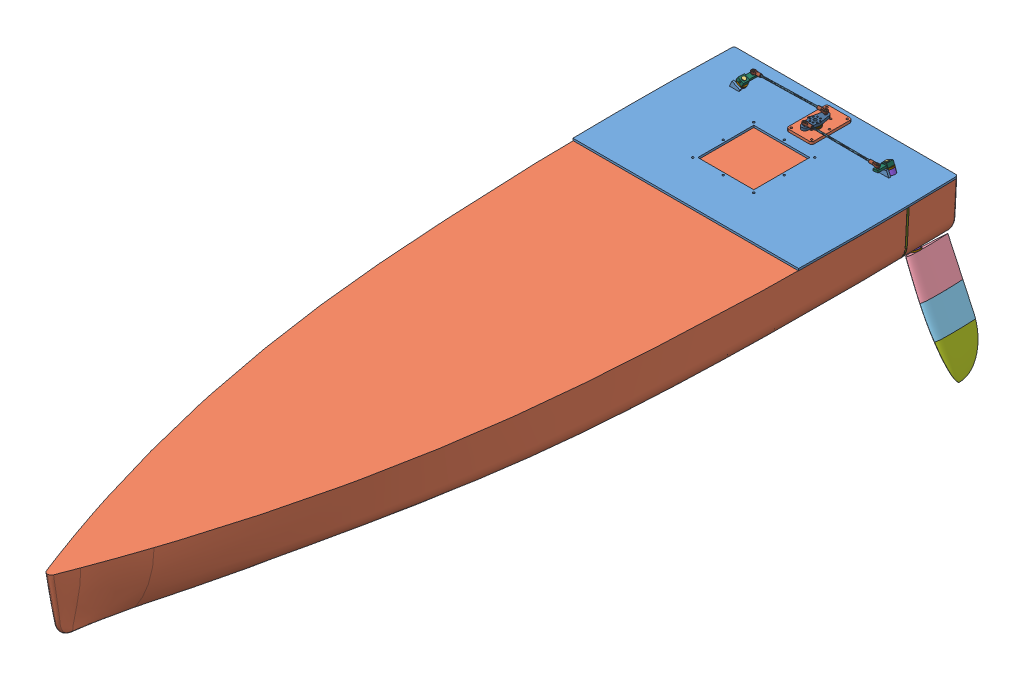
SolidWorks assembly TwinRudderBallJointLinkage, configuration Default. Lengths in mm.
Overall size (733.15 402.29 2004.6).
60 component instances, 27 part files, 103 mates.
Components (placement in the parent):
- BallJointLinkageRudderDeck-1: BallJointLinkageRudderDeck [Default] at origin size (590.36 222.07 2004.6)
- Hull 9.2 rounder bow-1: Hull 9.2 rounder bow [JustSolid] at origin size (590.36 218.85 2004.6)
- AssembledRudder-1: AssembledRudder [Default] at (243.1876 -116.4201 98.4134) x (0.029338 0.013681 -0.999476) z (0.422618 -0.906308 0) size (104.71 12.52 429.01)
  - BallJointLinkageRudderShaft-2: BallJointLinkageRudderShaft [Default] at (22.225 0 130.175) x (0 -1 0) z (1 0 0) size (9.53 285.75 9.53)
  - RudderDrivePlate-1: RudderDrivePlate [Default] at (30.1625 0 104.775) x (1 0 0) z (0 1 0) size (25.4 50.8 3.17) (hidden)
  - RudderTop-1: RudderTop [Default] at (-3.175 0 19.558) size (104.71 12.52 89.01)
  - RudderMiddle-1: RudderMiddle [Default] at (-3.175 0 19.558) size (104.7 12.44 76.26)
  - RudderTipCoupler-1: RudderTipCoupler [Default] at (21.971 1.397 184.5945) x (0 0 1) z (1 0 0) size (12.57 2.41 25.27)
  - RudderTip-1: RudderTip [Default] at (-3.175 0 19.431) size (101.87 12.42 88.9)
- AssembledRudder-2: AssembledRudder [Default] at (-244.4829 -115.8162 98.4137) x (0.028941 -0.013495 -0.99949) z (-0.422618 -0.906308 0) size (104.71 12.52 429.01)
  - BallJointLinkageRudderShaft-2: BallJointLinkageRudderShaft [Default] at (22.225 0 130.175) x (0 -1 0) z (1 0 0) size (9.53 285.75 9.53)
  - RudderDrivePlate-1: RudderDrivePlate [Default] at (30.1625 0 104.775) x (1 0 0) z (0 1 0) size (25.4 50.8 3.17) (hidden)
  - RudderTop-1: RudderTop [Default] at (-3.175 0 19.558) size (104.71 12.52 89.01)
  - RudderMiddle-1: RudderMiddle [Default] at (-3.175 0 19.558) size (104.7 12.44 76.26)
  - RudderTipCoupler-1: RudderTipCoupler [Default] at (21.971 1.397 184.5945) x (0 0 1) z (1 0 0) size (12.57 2.41 25.27)
  - RudderTip-1: RudderTip [Default] at (-3.175 0 19.431) size (101.87 12.42 88.9)
- GearedRudderTube-1: GearedRudderTube [Default] at (250.0925 -129.5254 76.2) x (0.604914 0.282076 -0.744656) z (0.674888 0.314705 0.667448) size (21.34 155.57 21.34)
- GearedRudderTube-2: GearedRudderTube [Default] at (-250.0925 -129.5254 76.2) x (-0.026603 0.012405 0.999569) z (-0.905917 0.422436 -0.029353) size (21.34 155.57 21.34)
- 6362K215_WATER-RESISTANT DRY-RUNNING SLEEVE BRNG-1: 6362K215_WATER-RESISTANT DRY-RUNNING SLEEVE BRNG [6362K215] at (183.0019 14.351 76.2) x (-0.758733 -0.353803 -0.546944) z (-0.4957 -0.231149 0.837169) size (22.23 12.7 22.23)
- 6362K215_WATER-RESISTANT DRY-RUNNING SLEEVE BRNG-2: 6362K215_WATER-RESISTANT DRY-RUNNING SLEEVE BRNG [6362K215] at (-251.4343 -132.4029 76.2) x (0.906308 -0.422618 0) z (0 0 1) size (22.23 12.7 22.23)
- 6362K215_WATER-RESISTANT DRY-RUNNING SLEEVE BRNG-3: 6362K215_WATER-RESISTANT DRY-RUNNING SLEEVE BRNG [6362K215] at (-183.0019 14.351 76.2) x (0.758733 -0.353803 0.546944) z (0.4957 -0.231149 -0.837169) size (22.23 12.7 22.23)
- 6362K215_WATER-RESISTANT DRY-RUNNING SLEEVE BRNG-4: 6362K215_WATER-RESISTANT DRY-RUNNING SLEEVE BRNG [6362K215] at (251.4343 -132.4029 76.2) x (0.906308 0.422618 0) z (0 0 1) size (22.23 12.7 22.23)
- ActoboticsRudderHorn-1: ActoboticsRudderHorn [Default] at (0 24.4475 76.835) x (-0.999706 0 -0.024255) z (-0.024255 0 0.999706) size (25.4 6.35 66.67)
- 585432_assembly-1: 585432_assembly [Default] at (-16.8337 40.4811 76.4373) x (-0.014796 -0.214042 -0.976712) z (0.999761 -0.018883 -0.011007) size (10.78 10.08 24.13) (flexible)
  - 585432 linkage-1: 585432 linkage [Default] at (-23.1721 -15.566 34.8679) size (10.78 7.16 24.13)
  - 585432 ball-1: 585432 ball [Default] at (-23.1721 -15.566 16.129) x (-0.120803 -0.045648 -0.991626) z (-0.969326 -0.209968 0.127752) size (6.4 6.4 6.4)
  - 585432 spacer-1: 585432 spacer [Default] at (-21.9978 -20.9242 16.2326) x (-0.975063 -0.212455 0.064148) z (0.214042 -0.976642 0.018883) size (6.35 6.35 2.98)
- 585432_assembly-2: 585432_assembly [Default] at (195.4216 46.4047 119.3729) x (0.014796 0.214042 0.976712) z (-0.999761 0.018883 0.011007) size (10.96 10.45 24.2) (flexible)
  - 585432 linkage-1: 585432 linkage [Default] at (-23.1721 -15.566 34.8679) size (10.78 7.16 24.13)
  - 585432 ball-1: 585432 ball [Default] at (-23.1721 -15.566 16.129) x (-0.376682 -0.099976 0.920932) z (0.900714 -0.27176 0.33891) size (6.4 6.4 6.4)
  - 585432 spacer-1: 585432 spacer [Default] at (-24.3593 -20.8173 15.0734) x (-0.695104 0.289437 -0.65807) z (-0.21639 -0.957158 -0.192417) size (6.35 6.35 2.98)
- 585432_assembly-3: 585432_assembly [Default] at (16.5009 47.5868 73.2471) x (0.002424 0.079161 0.996859) z (-0.999814 -0.018858 0.003929) size (10.78 9.4 24.13) (flexible)
  - 585432 linkage-1: 585432 linkage [Default] at (-23.1721 -15.566 34.8679) size (10.78 7.16 24.13)
  - 585432 ball-1: 585432 ball [Default] at (-23.1721 -15.566 16.129) x (0.986117 -0.081064 -0.144919) z (-0.145967 -0.007124 -0.989264) size (6.4 6.4 6.4)
  - 585432 spacer-1: 585432 spacer [Default] at (-23.6064 -21.0342 16.2325) x (0.223865 -0.036208 -0.973947) z (-0.079161 -0.996683 0.018858) size (6.35 6.35 2.98)
- 585432_assembly-4: 585432_assembly [Default] at (-194.4851 12.5673 76.5412) x (0.002424 0.079161 0.996859) z (0.999814 0.018858 -0.003929) size (10.78 10.06 24.15) (flexible)
  - 585432 linkage-1: 585432 linkage [Default] at (-23.1721 -15.566 34.8679) size (10.78 7.16 24.13)
  - 585432 ball-1: 585432 ball [Default] at (-23.1721 -15.566 16.129) x (-0.166025 -0.201578 -0.965299) z (0.983624 0.03577 -0.176646) size (6.4 6.4 6.4)
  - 585432 spacer-1: 585432 spacer [Default] at (-23.5569 -10.1958 15.0738) x (-0.81313 0.055593 0.579422) z (-0.070136 0.978819 -0.192339) size (6.35 6.35 2.98)
- 95412A373_18-8 STAINLESS STEEL THREADED ROD-3: 95412A373_18-8 STAINLESS STEEL THREADED ROD [95412A423] at (88.0315 28.2596 101.2516) x (0.999761 -0.018883 -0.011007) z (0.011544 0.028595 0.999524) size (153.89 3.54 4.05)
- 95412A373_18-8 STAINLESS STEEL THREADED ROD-4: 95412A373_18-8 STAINLESS STEEL THREADED ROD [95412A423] at (-90.0605 28.2236 51.7988) x (0.999814 0.018858 -0.003929) z (0.004833 -0.048104 0.998831) size (153.89 3.54 4.05)
- AngledRudderHorn-1: AngledRudderHorn [Default] at (180.7745 19.1277 76.2) x (-0.029338 -0.013681 0.999476) z (-0.905833 -0.422397 -0.032371) size (38.1 9.53 15.88)
- AngledRudderHorn-2: AngledRudderHorn [Default] at (-180.7745 19.1277 76.2) x (0.028941 -0.013495 -0.99949) z (0.905846 -0.422403 0.031932) size (38.1 9.53 15.88)
- RudderForward-1: RudderForward [Default] at (0 0 32.512) size (563.45 186.42 6.36)
- RudderTubeStabilizer-1: RudderTubeStabilizer [Default] at (-210.6261 -44.8894 64.4525) x (0 0 -1) z (0.906308 -0.422618 0) size (128.91 5.08 44.45)
- RudderTubeStabilizer-2: RudderTubeStabilizer [Default] at (210.6261 -44.8894 64.4525) x (0 0 -1) z (0.906308 0.422618 0) size (128.91 5.08 44.45)
- RudderTubeStabilizer-3: RudderTubeStabilizer [Default] at (-242.8296 -113.9501 64.4525) x (0 0 -1) z (0.906308 -0.422618 0) size (128.91 5.08 44.45)
- RudderTubeStabilizer-4: RudderTubeStabilizer [Default] at (242.8296 -113.9501 64.4525) x (0 0 -1) z (0.906308 0.422618 0) size (128.91 5.08 44.45)
- Transom-1: Transom [Default] at origin size (559.11 184.29 5.09) (hidden)
- Actobotics Servo Hub-1: Actobotics Servo Hub [Default] at (0 18.0975 76.835) x (0.93289 0 -0.360162) z (0.360162 0 0.93289) size (25.4 25.4 25.4)
- 13125K810_CHEMICAL-RESISTANT SHAFT SEAL-1: 13125K810_CHEMICAL-RESISTANT SHAFT SEAL [13125K81] at (0 9.3091 76.835) x (0 -1 0) z (-0.546944 0 0.837169) size (3.38 17.84 17.84)
- RudderServoDeckMountPlate-1: RudderServoDeckMountPlate [Default] at (0 5.08 66.675) x (-1 0 0) z (0 0 -1) size (63.5 6.35 101.6)
- 2639T170_ULTRA-LOW-FRICTION DRY-RUNNING SLEEVE BRNG-1: 2639T170_ULTRA-LOW-FRICTION DRY-RUNNING SLEEVE BRNG [2639T17] at (0 2.8575 76.835) x (1 0 0) z (0 -1 0) size (15.88 15.88 9.53)
- 7532K130_WATER-RESISTANT DRY-RUNNING THRUST BRNG-1: 7532K130_WATER-RESISTANT DRY-RUNNING THRUST BRNG [7532K13] at (0 12.2238 76.835) x (0.999852 0 -0.017211) z (0 -1 0) size (25.4 25.4 1.59)
- PDI 6621MG-1: PDI 6621MG [Standard] at (0 -50.62 46.433) x (0 0 1) z (-1 0 0) size (66.1 44.6 20.31)
- 91780A198_ALUM FEM THRDED HEX STANDOFF-1: 91780A198_ALUM FEM THRDED HEX STANDOFF [91780A309] at (4.7 -7.62 90.675) x (-0.837169 0 -0.546944) z (0 1 0) size (6.35 7.33 26.09)
- 91780A198_ALUM FEM THRDED HEX STANDOFF-2: 91780A198_ALUM FEM THRDED HEX STANDOFF [91780A309] at (-4.7 -7.62 90.675) x (-0.814097 0 -0.580728) z (0 1 0) size (6.35 7.33 26.09)
- 91780A198_ALUM FEM THRDED HEX STANDOFF-3: 91780A198_ALUM FEM THRDED HEX STANDOFF [91780A309] at (4.7 -7.62 42.675) x (1 0 0) z (0 -1 0) size (6.35 7.33 26.09)
- 91780A198_ALUM FEM THRDED HEX STANDOFF-4: 91780A198_ALUM FEM THRDED HEX STANDOFF [91780A309] at (-4.7 -7.62 42.675) x (1 0 0) z (0 -1 0) size (6.35 7.33 26.09)
- RudderServoDeckMountClamp-1: RudderServoDeckMountClamp [Default] at (0 0 66.675) x (-1 0 0) z (0 0 1) size (63.5 6.35 101.6)
Mates (geometry in assembly coordinates):
- Concentric155: concentric anti-aligned: circle of GearedRudderTube-1; circle of 6362K215_WATER-RESISTANT DRY-RUNNING SLEEVE BRNG-1
- Coincident78: coincident anti-aligned: plane of GearedRudderTube-1 through (184.3437 11.4735 76.2) normal (-0.422618 0.906308 0); circle of 6362K215_WATER-RESISTANT DRY-RUNNING SLEEVE BRNG-1
- Concentric157: concentric aligned: cylinder of GearedRudderTube-1 through (184.3437 11.4735 76.2) axis (0.422618 -0.906308 0) radius 10.668; cylinder of 6362K215_WATER-RESISTANT DRY-RUNNING SLEEVE BRNG-4 through (246.0671 -120.8928 76.2) axis (0.422618 -0.906308 0) radius 7.9375
- Coincident79: coincident aligned: circle of GearedRudderTube-1; plane of 6362K215_WATER-RESISTANT DRY-RUNNING SLEEVE BRNG-4 through (250.0925 -129.5254 76.2) normal (-0.422618 0.906308 0)
- Concentric158: concentric anti-aligned: circle of GearedRudderTube-2; circle of 6362K215_WATER-RESISTANT DRY-RUNNING SLEEVE BRNG-3
- Coincident80: coincident anti-aligned: plane of GearedRudderTube-2 through (-184.3437 11.4735 76.2) normal (0.422618 0.906308 0); plane of 6362K215_WATER-RESISTANT DRY-RUNNING SLEEVE BRNG-3 through (-184.3437 11.4735 76.2) normal (-0.422618 -0.906308 0)
- Concentric159: concentric aligned: cylinder of GearedRudderTube-2 through (-184.3437 11.4735 76.2) axis (-0.422618 -0.906308 0) radius 10.668; cylinder of 6362K215_WATER-RESISTANT DRY-RUNNING SLEEVE BRNG-2 through (-246.0671 -120.8928 76.2) axis (-0.422618 -0.906308 0) radius 7.9375
- Coincident81: coincident aligned: circle of GearedRudderTube-2; plane of 6362K215_WATER-RESISTANT DRY-RUNNING SLEEVE BRNG-2 through (-250.0925 -129.5254 76.2) normal (0.422618 0.906308 0)
- Concentric160: concentric aligned: cylinder of BallJointLinkageRudderDeck-1 through (10.6776 429.698 76.2) axis (-0.422618 -0.906308 0) radius 10.668; cylinder of GearedRudderTube-2 through (-184.3437 11.4735 76.2) axis (-0.422618 -0.906308 0) radius 10.668
- Concentric161: concentric anti-aligned: cylinder of BallJointLinkageRudderDeck-1 through (201.5381 -25.4 76.2) axis (-0.422618 0.906308 0) radius 10.668; cylinder of GearedRudderTube-1 through (184.3437 11.4735 76.2) axis (0.422618 -0.906308 0) radius 10.668
- Coincident84: coincident aligned: plane of BallJointLinkageRudderDeck-1 through (27.1885 -58.306 91.948) normal (-0.422618 0.906308 0); plane of 6362K215_WATER-RESISTANT DRY-RUNNING SLEEVE BRNG-1 through (183.0019 14.351 76.2) normal (-0.422618 0.906308 0)
- Coincident85: coincident aligned: plane of BallJointLinkageRudderDeck-1 through (-27.1885 -58.306 91.948) normal (0.422618 0.906308 0); plane of 6362K215_WATER-RESISTANT DRY-RUNNING SLEEVE BRNG-3 through (-183.0019 14.351 76.2) normal (0.422618 0.906308 0)
- Distance1: distance = 1.5875 mm anti-aligned: plane of ? through (-246.7964 -150.2601 171.8322) normal (0.422618 0.906308 0); plane of 6362K215_WATER-RESISTANT DRY-RUNNING SLEEVE BRNG-2 through (-249.1084 -147.4304 146.6463) normal (-0.422618 -0.906308 0)
- Distance2: distance = 1.5875 mm anti-aligned: plane of 6362K215_WATER-RESISTANT DRY-RUNNING SLEEVE BRNG-4 through (253.7603 -147.4304 146.6463) normal (0.422618 -0.906308 0); plane of ? through (257.2883 -147.5369 171.8499) normal (-0.422618 0.906308 0)
- Coincident126: coincident aligned: line of BallJointLinkageRudderDeck-1 through (274.4604 0 0) axis (-1 0 0); line of Hull 9.2 rounder bow-1 through (548.9208 274.4604 0) axis (0 -1 0)
- Parallel1: parallel aligned: plane of BallJointLinkageRudderDeck-1 through (274.4604 5.08 0) normal (0 0 -1); plane of Hull 9.2 rounder bow-1 through (0 0 0) normal (0 0 -1)
- Concentric184: concentric anti-aligned: cylinder of 585432_assembly-1/585432 linkage-1 through (18.1183 29.5801 102.0213) axis (-0.999761 0.018883 0.011007) radius 3.5814; cylinder of 585432_assembly-2/585432 linkage-1 through (159.9688 26.9009 100.4596) axis (0.999761 -0.018883 -0.011007) radius 3.5814
- Concentric186: concentric anti-aligned: cylinder of 585432_assembly-3/585432 linkage-1 through (-18.1193 29.5805 51.5161) axis (0.999814 0.018858 -0.003929) radius 3.5814; cylinder of 585432_assembly-4/585432 linkage-1 through (-159.9774 26.9049 52.0736) axis (-0.999814 -0.018858 0.003929) radius 3.5814
- Distance4: distance = 141.8844 mm anti-aligned: plane of 585432_assembly-1/585432 linkage-1 through (18.1183 29.5801 102.0213) normal (0.999761 -0.018883 -0.011007); plane of 585432_assembly-2/585432 linkage-1 through (159.9688 26.9009 100.4596) normal (-0.999761 0.018883 0.011007)
- Distance5: distance = 141.8844 mm anti-aligned: plane of 585432_assembly-3/585432 linkage-1 through (-18.1193 29.5805 51.5161) normal (-0.999814 -0.018858 0.003929); plane of 585432_assembly-4/585432 linkage-1 through (-159.9774 26.9049 52.0736) normal (0.999814 0.018858 -0.003929)
- Concentric188: concentric aligned: cylinder of 585432_assembly-2/585432 linkage-1 through (159.9688 26.9009 100.4596) axis (0.999761 -0.018883 -0.011007) radius 3.5814; cylinder of 95412A373_18-8 STAINLESS STEEL THREADED ROD-3 through (11.8497 29.6985 102.0903) axis (0.999761 -0.018883 -0.011007) radius 1.7526
- Concentric189: concentric aligned: cylinder of 585432_assembly-3/585432 linkage-1 through (-18.1193 29.5805 51.5161) axis (0.999814 0.018858 -0.003929) radius 3.5814; cylinder of 95412A373_18-8 STAINLESS STEEL THREADED ROD-4 through (-166.2463 26.7866 52.0982) axis (0.999814 0.018858 -0.003929) radius 1.7526
- Tangent1: tangent: curve of 585432_assembly-4/585432 linkage-1; plane of 95412A373_18-8 STAINLESS STEEL THREADED ROD-4 through (-166.2463 26.7866 52.0982) normal (-0.999814 -0.018858 0.003929)
- Tangent3: tangent: curve of ?; plane of 95412A373_18-8 STAINLESS STEEL THREADED ROD-3 through (11.8497 29.6985 102.0903) normal (-0.999761 0.018883 0.011007)
- Concentric194: concentric anti-aligned: cylinder of 585432_assembly-4/585432 ball-1 through (-178.1566 29.7031 52.1208) axis (-0.173768 -0.984752 0.008265) radius 1.7399; cylinder of AngledRudderHorn-2 through (-179.6661 21.1487 52.1926) axis (0.173768 0.984752 -0.008265) radius 1.3526
- Coincident132: coincident anti-aligned: plane of 585432_assembly-4/585432 spacer-1 through (-179.6661 21.1487 52.1926) normal (-0.173768 -0.984752 0.008265); plane of AngledRudderHorn-2 through (-173.2371 19.9642 46.2291) normal (0.173768 0.984752 -0.008265)
- Concentric195: concentric aligned: cylinder of 585432_assembly-2/585432 spacer-1 through (179.6565 21.1443 100.2074) axis (-0.173771 0.98475 0.008378) radius 3.175; cylinder of AngledRudderHorn-1 through (179.6565 21.1443 100.2074) axis (-0.173771 0.98475 0.008378) radius 1.3526
- Coincident133: coincident anti-aligned: plane of 585432_assembly-2/585432 spacer-1 through (179.6565 21.1443 100.2074) normal (0.173771 -0.98475 -0.008378); plane of AngledRudderHorn-1 through (173.2251 19.9587 106.1681) normal (-0.173771 0.98475 0.008378)
- Coincident135: coincident aligned: plane of 585432_assembly-1/585432 linkage-1 through (-0.6504 27.8501 102.6847) normal (-0.016087 -0.976642 0.21427); plane of 585432_assembly-2/585432 linkage-1 through (178.6688 24.4633 100.7105) normal (-0.016087 -0.976642 0.21427)
- Coincident136: coincident aligned: plane of 585432_assembly-3/585432 linkage-1 through (0.5753 32.0604 51.2737) normal (-0.01911 0.996683 -0.079101); plane of 585432_assembly-4/585432 linkage-1 through (-178.7535 28.678 51.9784) normal (-0.01911 0.996683 -0.079101)
- Coincident138: coincident anti-aligned: plane of BallJointLinkageRudderDeck-1 through (283.0025 0 202.5097) normal (0 -1 0); plane of RudderForward-1 through (-281.719 0 123.825) normal (0 1 0)
- Concentric196: concentric aligned: cylinder of GearedRudderTube-1 through (184.3437 11.4735 76.2) axis (0.422618 -0.906308 0) radius 10.668; cylinder of RudderTubeStabilizer-4 through (240.6827 -109.346 76.2) axis (0.422618 -0.906308 0) radius 10.668
- Concentric197: concentric aligned: cylinder of GearedRudderTube-1 through (184.3437 11.4735 76.2) axis (0.422618 -0.906308 0) radius 10.668; cylinder of RudderTubeStabilizer-2 through (208.4792 -40.2854 76.2) axis (0.422618 -0.906308 0) radius 10.668
- Concentric198: concentric aligned: cylinder of GearedRudderTube-2 through (-184.3437 11.4735 76.2) axis (-0.422618 -0.906308 0) radius 10.668; cylinder of RudderTubeStabilizer-3 through (-240.6827 -109.346 76.2) axis (-0.422618 -0.906308 0) radius 10.668
- Concentric199: concentric aligned: cylinder of GearedRudderTube-2 through (-184.3437 11.4735 76.2) axis (-0.422618 -0.906308 0) radius 10.668; cylinder of RudderTubeStabilizer-1 through (-208.4792 -40.2854 76.2) axis (-0.422618 -0.906308 0) radius 10.668
- Parallel4: parallel aligned: plane of RudderForward-1 through (-194.7545 -152.0833 123.825) normal (0 0 -1); plane of RudderTubeStabilizer-2 through (208.4792 -40.2854 5.08) normal (0 0 -1)
- Parallel5: parallel aligned: plane of RudderForward-1 through (-194.7545 -152.0833 123.825) normal (0 0 -1); plane of RudderTubeStabilizer-4 through (240.6827 -109.346 5.08) normal (0 0 -1)
- Coincident153: coincident aligned: plane of Hull 9.2 rounder bow-1 through (0 0 0) normal (1 0 0); plane of RudderForward-1 through (0 0 32.512) normal (1 0 0)
- Coincident160: coincident aligned: plane of Hull 9.2 rounder bow-1 through (0 0 0) normal (0 0 -1); plane of Transom-1 through (-193.7444 -151.0129 0) normal (0 0 -1)
- Coincident161: coincident anti-aligned: line of BallJointLinkageRudderDeck-1 through (274.4604 0 0) axis (-1 0 0); line of Transom-1 through (559.0992 -279.5496 0) axis (0 1 0)
- Coincident162: coincident anti-aligned: plane of BallJointLinkageRudderDeck-1 through (283.0025 0 202.5097) normal (0 -1 0); plane of Transom-1 through (-279.5496 0 0) normal (0 1 0)
- Coincident163: coincident aligned: plane of Hull 9.2 rounder bow-1 through (0 0 0) normal (1 0 0); plane of Transom-1 through (0 0 0) normal (1 0 0)
- Concentric205: concentric aligned: cylinder of AssembledRudder-1/BallJointLinkageRudderShaft-2 through (178.0908 24.8827 76.2) axis (0.422618 -0.906308 0) radius 4.7625; cylinder of GearedRudderTube-1 through (184.3437 11.4735 76.2) axis (0.422618 -0.906308 0) radius 10.668
- Concentric206: concentric aligned: cylinder of AssembledRudder-2/BallJointLinkageRudderShaft-2 through (-178.0908 24.8827 76.2) axis (-0.422618 -0.906308 0) radius 4.7625; cylinder of GearedRudderTube-2 through (-184.3437 11.4735 76.2) axis (-0.422618 -0.906308 0) radius 10.668
- Concentric207: concentric anti-aligned: cylinder of AssembledRudder-1/BallJointLinkageRudderShaft-2 through (180.6347 19.0625 80.96) axis (-0.029338 -0.013681 0.999476) radius 1.7272; cylinder of AngledRudderHorn-1 through (181.0073 19.2363 68.2667) axis (0.029338 0.013681 -0.999476) radius 2.2479
- Concentric208: concentric anti-aligned: cylinder of AssembledRudder-1/BallJointLinkageRudderShaft-2 through (178.0908 24.8827 76.2) axis (0.422618 -0.906308 0) radius 4.7625; cylinder of AngledRudderHorn-1 through (178.7617 23.444 76.2) axis (-0.422618 0.906308 0) radius 4.7625
- Concentric209: concentric aligned: cylinder of AssembledRudder-2/BallJointLinkageRudderShaft-2 through (-180.9123 19.192 80.9601) axis (-0.028941 0.013495 0.99949) radius 1.7272; cylinder of AngledRudderHorn-2 through (-181.0042 19.2348 84.1335) axis (-0.028941 0.013495 0.99949) radius 2.2479
- Concentric210: concentric anti-aligned: cylinder of AssembledRudder-2/BallJointLinkageRudderShaft-2 through (-178.0908 24.8827 76.2) axis (-0.422618 -0.906308 0) radius 4.7625; cylinder of AngledRudderHorn-2 through (-178.7617 23.444 76.2) axis (0.422618 0.906308 0) radius 4.7625
- Parallel6: parallel anti-aligned: plane of RudderTubeStabilizer-1 through (-208.4792 -40.2854 5.08) normal (0 0 -1); plane of Transom-1 through (-193.7444 -151.0129 5.08) normal (0 0 1)
- Parallel7: parallel anti-aligned: plane of RudderTubeStabilizer-3 through (-240.6827 -109.346 5.08) normal (0 0 -1); plane of Transom-1 through (-193.7444 -151.0129 5.08) normal (0 0 1)
- Coincident166: coincident: line of RudderTubeStabilizer-2 through (228.6219 -30.8927 0) axis (-0.906308 -0.422618 0); plane of Transom-1 through (228.6219 -30.8927 1993.9001) normal (0.422618 -0.906308 0)
- Coincident167: coincident: line of RudderTubeStabilizer-4 through (260.8254 -99.9533 0) axis (-0.906308 -0.422618 0); plane of Transom-1 through (255.0704 -102.637 1993.9001) normal (0.422618 -0.906308 0)
- Coincident168: coincident: line of RudderTubeStabilizer-1 through (-228.6219 -30.8927 0) axis (0.906308 -0.422618 0); plane of Transom-1 through (-228.6219 -30.8927 5.085) normal (-0.422618 -0.906308 0)
- Coincident169: coincident: line of RudderTubeStabilizer-3 through (-260.8254 -99.9533 0) axis (0.906308 -0.422618 0); plane of Transom-1 through (-255.0704 -102.637 5.085) normal (-0.422618 -0.906308 0)
- Concentric211: concentric aligned: cylinder of ? through (-3.4241 33.3325 161.8044) axis (0 1 0) radius 2.25; cylinder of ? through (-3.4241 33.2325 161.8044) axis (0 1 0) radius 1.1906
- Concentric212: concentric aligned: cylinder of ? through (7.0759 33.3325 161.8044) axis (0 1 0) radius 2.25; cylinder of ? through (7.0759 33.2325 161.8044) axis (0 1 0) radius 1.1906
- Coincident171: coincident anti-aligned: plane of ?; plane of ? through (27.7259 33.2325 188.8103) normal (0 1 0)
- Coincident178: coincident anti-aligned: plane of BallJointLinkageRudderDeck-1 through (285.3463 -9.9475 276.1309) normal (0 1 0); plane of ? through (2.5914 -9.9475 99.9103) normal (0 -1 0)
- Coincident179: coincident anti-aligned: plane of ? through (-23.0741 33.2325 99.9103) normal (0 0 -1); plane of ? through (2.5914 -9.9475 99.9103) normal (0 0 1)
- Coincident186: coincident anti-aligned: line of ? through (-3.7586 68.1575 94.8303) axis (0 0 1); line of ? through (-3.7586 68.1575 99.9103) axis (0 0 -1)
- Coincident187: coincident aligned: line of ? through (8.9414 68.1575 99.9103) axis (-1 0 0); line of ? through (8.9414 68.1575 99.9103) axis (-1 0 0)
- Coincident197: coincident aligned: plane of BallJointLinkageRudderDeck-1 through (0 0 0) normal (1 0 0); plane of Hull 9.2 rounder bow-1 through (0 0 0) normal (1 0 0)
- Concentric215: concentric anti-aligned: cylinder of ActoboticsRudderHorn-1 through (3.522 18.0975 85.9577) axis (0 -1 0) radius 1.8986; cylinder of Actobotics Servo Hub-1 through (3.522 18.0975 85.9577) axis (0 1 0) radius 1.3526
- Concentric216: concentric anti-aligned: cylinder of ActoboticsRudderHorn-1 through (-3.9603 18.0975 85.7762) axis (0 -1 0) radius 1.8986; cylinder of Actobotics Servo Hub-1 through (-3.9603 18.0975 85.7762) axis (0 1 0) radius 1.3526
- Coincident199: coincident anti-aligned: plane of ActoboticsRudderHorn-1 through (0 18.0975 76.835) normal (0 -1 0); plane of Actobotics Servo Hub-1 through (11.8477 18.0975 72.2609) normal (0 1 0)
- Concentric217: concentric aligned: cylinder of ActoboticsRudderHorn-1 through (-0.6161 18.0975 102.2275) axis (0 -1 0) radius 1.3526; cylinder of 585432_assembly-1/585432 ball-1 through (-0.6161 33.1343 102.2275) axis (0 -1 0) radius 1.7399
- Coincident201: coincident anti-aligned: plane of ActoboticsRudderHorn-1 through (0 24.4475 76.835) normal (0 1 0); plane of 585432_assembly-1/585432 spacer-1 through (-0.6161 24.4475 102.2275) normal (0 -1 0)
- Coincident202: coincident anti-aligned: plane of ActoboticsRudderHorn-1 through (0 24.4475 76.835) normal (0 1 0); plane of 585432_assembly-3/585432 spacer-1 through (0.6161 24.4475 51.4425) normal (0 -1 0)
- Concentric218: concentric aligned: cylinder of ActoboticsRudderHorn-1 through (0.6161 18.0975 51.4425) axis (0 -1 0) radius 1.3526; cylinder of 585432_assembly-3/585432 ball-1 through (0.6161 33.1343 51.4425) axis (0 -1 0) radius 1.7399
- Concentric219: concentric anti-aligned: cylinder of Actobotics Servo Hub-1 through (0 18.0975 76.835) axis (0 1 0) radius 6.35; cone of 13125K810_CHEMICAL-RESISTANT SHAFT SEAL-1 through (0 8.2956 76.835) axis (0 -1 0)
- Concentric221: concentric anti-aligned: cylinder of ? through (2.3259 -28.2907 152.9963) axis (0 -1 0) radius 6.725; cylinder of Actobotics Servo Hub-1 through (2.3259 0.3268 152.9963) axis (0 1 0) radius 6.35
- Coincident206: coincident anti-aligned: plane of RudderForward-1 through (-194.7545 -152.0833 123.825) normal (0 0 -1); plane of RudderTubeStabilizer-2 through (208.4792 -40.2854 123.825) normal (0 0 1)
- Concentric222: concentric anti-aligned: cylinder of RudderServoDeckMountPlate-1 through (0 13.0175 76.835) axis (0 -1 0) radius 7.9375; cylinder of 2639T170_ULTRA-LOW-FRICTION DRY-RUNNING SLEEVE BRNG-1 through (0 -1.905 76.835) axis (0 1 0) radius 7.9375
- Coincident207: coincident aligned: plane of RudderServoDeckMountPlate-1 through (0 7.62 76.835) normal (0 1 0); plane of 2639T170_ULTRA-LOW-FRICTION DRY-RUNNING SLEEVE BRNG-1 through (0 7.62 76.835) normal (0 1 0)
- Concentric223: concentric aligned: cylinder of Actobotics Servo Hub-1 through (0 18.0975 76.835) axis (0 1 0) radius 6.35; cylinder of 2639T170_ULTRA-LOW-FRICTION DRY-RUNNING SLEEVE BRNG-1 through (0 -1.905 76.835) axis (0 1 0) radius 6.35
- Coincident208: coincident anti-aligned: plane of 13125K810_CHEMICAL-RESISTANT SHAFT SEAL-1 through (7.149 7.62 81.5056) normal (0 -1 0); plane of RudderServoDeckMountPlate-1 through (0 7.62 76.835) normal (0 1 0)
- Parallel10: parallel anti-aligned: plane of ? through (11.6588 -33.2907 164.0879) normal (0.996313 0 0.085792); plane of RudderServoDeckMountPlate-1
- Concentric224: concentric anti-aligned: circle of Actobotics Servo Hub-1; circle of 7532K130_WATER-RESISTANT DRY-RUNNING THRUST BRNG-1
- Coincident209: coincident anti-aligned: plane of Actobotics Servo Hub-1 through (5.9239 13.0175 74.548) normal (0 -1 0); plane of 7532K130_WATER-RESISTANT DRY-RUNNING THRUST BRNG-1 through (0 13.0175 76.835) normal (0 1 0)
- Distance6: distance = 22.225 mm anti-aligned: plane of ? through (-8.1823 -38.0907 155.5543) normal (0 1 0); plane of RudderServoDeckMountPlate-1 through (3.1431 -15.8657 143.5065) normal (0 -1 0)
- Concentric225: concentric anti-aligned: cylinder of Actobotics Servo Hub-1 through (0 18.0975 76.835) axis (0 1 0) radius 6.35; cylinder of PDI 6621MG-1 through (0 -10.17 76.835) axis (0 -1 0) radius 6.525
- Parallel11: parallel anti-aligned: plane of RudderForward-1 through (-194.7545 -152.0833 123.825) normal (0 0 -1); plane of PDI 6621MG-1 through (10.098 -22.92 86.933) normal (0 0 1)
- Concentric226: concentric aligned: cylinder of RudderServoDeckMountPlate-1 through (-4.7 5.08 90.675) axis (0 -1 0) radius 2.2479; circle of 91780A198_ALUM FEM THRDED HEX STANDOFF-2
- Concentric227: concentric aligned: cylinder of RudderServoDeckMountPlate-1 through (4.7 5.08 90.675) axis (0 -1 0) radius 2.2479; circle of 91780A198_ALUM FEM THRDED HEX STANDOFF-1
- Coincident215: coincident anti-aligned: plane of RudderServoDeckMountPlate-1 through (0 5.08 66.675) normal (0 -1 0); plane of 91780A198_ALUM FEM THRDED HEX STANDOFF-2 through (-6.8291 5.08 93.6596) normal (0 1 0)
- Coincident216: coincident anti-aligned: plane of RudderServoDeckMountPlate-1 through (0 5.08 66.675) normal (0 -1 0); plane of 91780A198_ALUM FEM THRDED HEX STANDOFF-1 through (2.6948 5.08 93.7442) normal (0 1 0)
- Concentric228: concentric anti-aligned: cylinder of RudderServoDeckMountPlate-1 through (4.7 5.08 42.675) axis (0 -1 0) radius 2.2479; circle of 91780A198_ALUM FEM THRDED HEX STANDOFF-3
- Coincident217: coincident anti-aligned: plane of RudderServoDeckMountPlate-1 through (0 5.08 66.675) normal (0 -1 0); plane of 91780A198_ALUM FEM THRDED HEX STANDOFF-3 through (4.7 5.08 46.3412) normal (0 1 0)
- Concentric229: concentric anti-aligned: cylinder of RudderServoDeckMountPlate-1 through (-4.7 5.08 42.675) axis (0 -1 0) radius 2.2479; circle of 91780A198_ALUM FEM THRDED HEX STANDOFF-4
- Coincident218: coincident anti-aligned: plane of RudderServoDeckMountPlate-1 through (0 5.08 66.675) normal (0 -1 0); plane of 91780A198_ALUM FEM THRDED HEX STANDOFF-4 through (-4.7 5.08 46.3412) normal (0 1 0)
- Parallel12: parallel aligned: plane of RudderServoDeckMountPlate-1 through (-31.75 11.43 15.875) normal (-1 0 0); plane of PDI 6621MG-1 through (-10.098 -22.92 46.435) normal (-1 0 0)
- Distance8: distance = 1.5875 mm anti-aligned: plane of AssembledRudder-2/RudderTop-1 through (-252.8403 -133.4989 101.587) normal (0.422618 0.906308 0); plane of 6362K215_WATER-RESISTANT DRY-RUNNING SLEEVE BRNG-2 through (-251.4343 -132.4029 76.2) normal (-0.422618 -0.906308 0)
- Distance9: distance = 1.5875 mm anti-aligned: plane of AssembledRudder-1/RudderTop-1 through (251.36 -134.1891 101.5867) normal (-0.422618 0.906308 0); plane of 6362K215_WATER-RESISTANT DRY-RUNNING SLEEVE BRNG-4 through (251.4343 -132.4029 76.2) normal (0.422618 -0.906308 0)
- Coincident219: coincident anti-aligned: plane of RudderServoDeckMountPlate-1 through (0 11.43 66.675) normal (0 1 0); plane of 7532K130_WATER-RESISTANT DRY-RUNNING THRUST BRNG-1 through (0 11.43 76.835) normal (0 -1 0)
- Coincident220: coincident anti-aligned: plane of BallJointLinkageRudderDeck-1 through (283.0025 5.08 202.5097) normal (0 1 0); plane of RudderServoDeckMountPlate-1 through (0 5.08 66.675) normal (0 -1 0)
- Coincident221: coincident anti-aligned: plane of BallJointLinkageRudderDeck-1 through (283.0025 0 202.5097) normal (0 -1 0); plane of RudderServoDeckMountClamp-1 through (0 0 66.675) normal (0 1 0)
- Concentric232: concentric aligned: cylinder of BallJointLinkageRudderDeck-1 through (-25.4 5.08 22.225) axis (0 1 0) radius 1.7272; cylinder of RudderServoDeckMountPlate-1 through (-25.4 11.43 22.225) axis (0 1 0) radius 2.5527
- Coincident222: coincident anti-aligned: plane of PDI 6621MG-1 through (4.7 -20.32 42.684) normal (0 1 0); plane of 91780A198_ALUM FEM THRDED HEX STANDOFF-3 through (4.7 -20.32 46.3412) normal (0 -1 0)
- Coincident223: coincident aligned: plane of BallJointLinkageRudderDeck-1 through (0 0 0) normal (0 0 1); plane of assembly through (0 0 0) normal (0 0 1)
- Coincident224: coincident aligned: plane of BallJointLinkageRudderDeck-1 through (0 0 0) normal (0 1 0); plane of assembly through (0 0 0) normal (0 1 0)
- Coincident225: coincident aligned: plane of BallJointLinkageRudderDeck-1 through (0 0 0) normal (1 0 0); plane of assembly through (0 0 0) normal (1 0 0)
- Concentric233: concentric aligned: cylinder of BallJointLinkageRudderDeck-1 through (25.4 5.08 22.225) axis (0 1 0) radius 1.7272; cylinder of RudderServoDeckMountClamp-1 through (25.4 -6.35 22.225) axis (0 1 0) radius 6.35
- Concentric234: concentric aligned: cylinder of BallJointLinkageRudderDeck-1 through (-25.4 5.08 22.225) axis (0 1 0) radius 1.7272; cylinder of RudderServoDeckMountClamp-1 through (-25.4 -6.35 22.225) axis (0 1 0) radius 6.35
